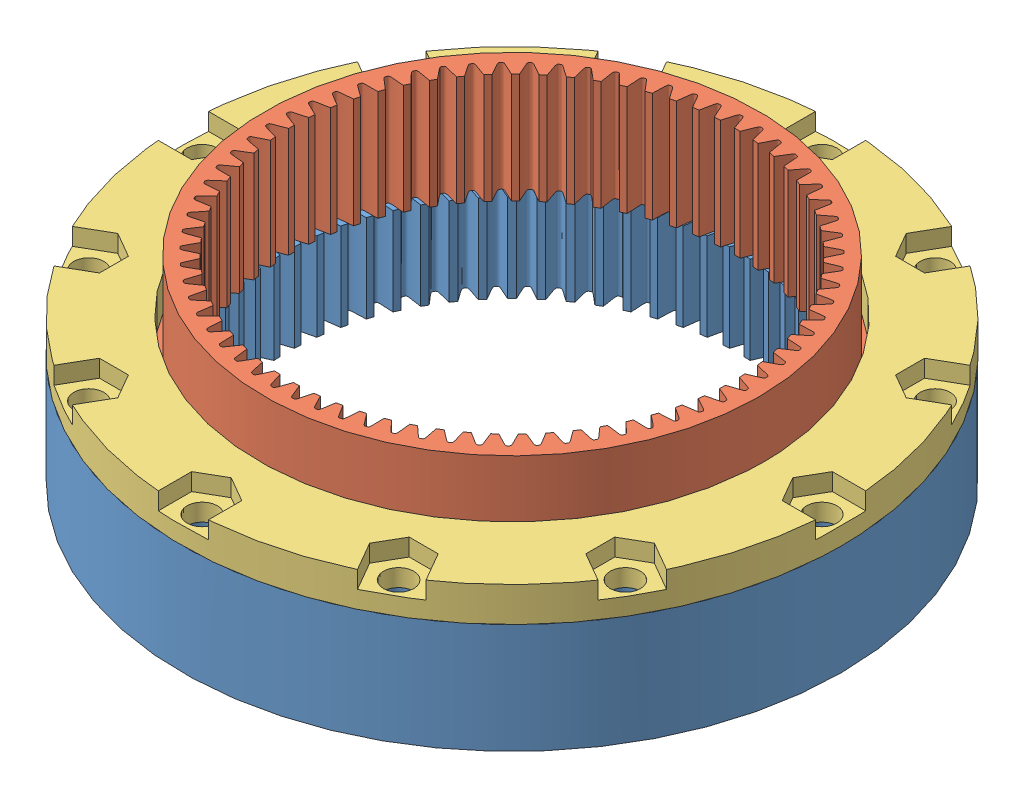
SolidWorks assembly ring_assem, configuration Default. Lengths in mm.
Overall size (76.2 22.86 82.49).
3 component instances, 3 part files, 4 mates.
Components (placement in the parent):
- input_ring-1: input_ring [Ring_Gear_Follower01] at (48.342 31.5802 53.5506) x (1 0 0) z (0 1 0) size (76.2 79.65 12.7)
- output_ring-1: output_ring [Ring_Gear_Follower02] at (48.342 41.7402 53.5506) x (1 0 0) z (0 1 0) size (66.04 66.04 12.7)
- ring_cap-1: ring_cap [Default] at (48.342 37.9302 53.5506) x (1 0 0) z (0 1 0) size (76.2 82.49 4)
Mates (geometry in assembly coordinates):
- Concentric1: concentric aligned: cylinder of input_ring-1 through (48.342 35.3902 53.5506) axis (0 1 0) radius 33.655; cylinder of output_ring-1 through (48.342 35.3902 53.5506) axis (0 1 0) radius 33.02
- Coincident2: coincident aligned: plane of input_ring-1 through (48.342 37.9302 27.5389) normal (0 1 0); plane of output_ring-1 through (48.342 37.9302 53.5506) normal (0 1 0)
- Concentric2: concentric anti-aligned: cylinder of output_ring-1 through (48.342 37.9302 53.5506) axis (0 1 0) radius 28.575; cylinder of ring_cap-1 through (48.342 41.9302 53.5506) axis (0 -1 0) radius 29.21
- Coincident3: coincident anti-aligned: plane of input_ring-1 through (48.342 37.9302 27.5389) normal (0 1 0); plane of ring_cap-1 through (48.342 37.9302 53.5506) normal (0 -1 0)
